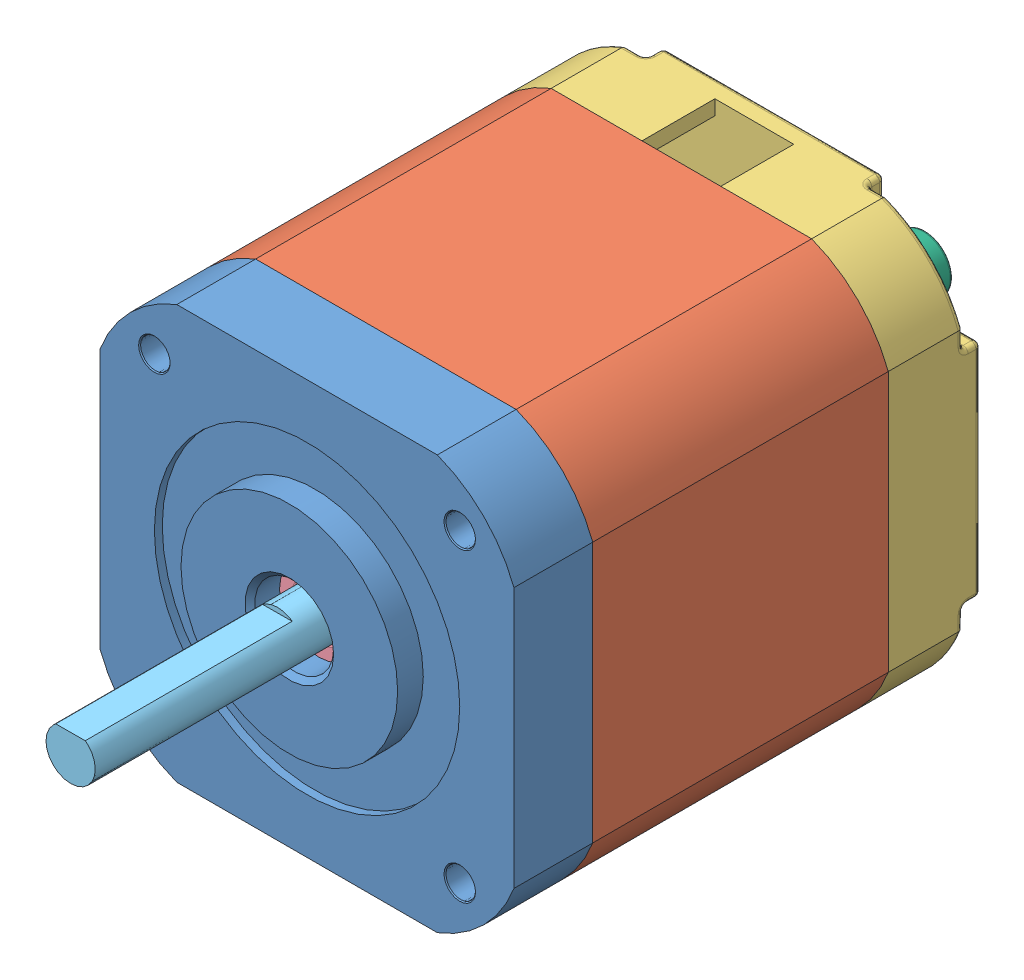
SolidWorks assembly Nema 17, configuration Default. Lengths in mm.
Overall size (42 42 71.95).
10 component instances, 6 part files, 23 mates.
Components (placement in the parent):
- Part1^Nema 17-1: Part1^Nema 17 [Default] at origin size (42 42 10.8) (virtual)
- Part2^Nema 17-1: Part2^Nema 17 [Default] at (0 0 -8) x (-1 0 0) z (0 0 -1) size (42 42 30) (virtual)
- Part3^Nema 17-1: Part3^Nema 17 [Default] at (0 0 -38) x (-1 0 0) z (0 0 -1) size (42 42 10.2) (virtual)
- radial ball bearing_68_din-1: radial ball bearing_68_din [DIN 625 - 625 - 8,SI,NC,8_68] at (0 0 -3.7) x (0 0 -1) z (1 0 0) size (5 16 16)
- radial ball bearing_68_din-2: radial ball bearing_68_din [DIN 625 - 625 - 8,SI,NC,8_68] at (0 0 -41.9) x (0 0 -1) z (0.878806 0.477179 0) size (5 16 16)
- Part4^Nema 17-1: Part4^Nema 17 [Default] at (0 0 -44.5) x (0.99998 0.006291 0) z (0 0 1) size (5 5 68.5) (virtual)
- pan head cross recess screw_din-3: pan head cross recess screw_din [ISO 7045 - M3 x 40 - Z --- 30N] at (-15.5 15.5 -48) x (0 0 1) z (-1 0 0) size (42.35 5.6 5.6)
- pan head cross recess screw_din-4: pan head cross recess screw_din [ISO 7045 - M3 x 40 - Z --- 30N] at (-15.5 -15.5 -48) x (0 0 1) z (-1 0 0) size (42.35 5.6 5.6)
- pan head cross recess screw_din-5: pan head cross recess screw_din [ISO 7045 - M3 x 40 - Z --- 30N] at (15.5 -15.5 -48) x (0 0 1) z (-1 0 0) size (42.35 5.6 5.6)
- pan head cross recess screw_din-6: pan head cross recess screw_din [ISO 7045 - M3 x 40 - Z --- 30N] at (15.5 15.5 -48) x (0 0 1) z (-1 0 0) size (42.35 5.6 5.6)
Mates (geometry in assembly coordinates):
- Coincident4: coordinate: point of Part1^Nema 17-1; point of assembly
- InPlace2: in place: plane of Part1^Nema 17-1 through (0 0 -8) normal (0 0 -1); plane of Part2^Nema 17-1 through (0 0 -8) normal (0 0 -1); moOrthogonalPlaneRef_w of Part1^Nema 17-1 through (0 0 -8) normal (0 0 -1); unknown of Part2^Nema 17-1; plane of Part1^Nema 17-1 through (0 0 -8) normal (0 0 -1); plane of Part2^Nema 17-1 through (0 0 -8) normal (-1 0 0); plane of Part1^Nema 17-1 through (0 0 -8) normal (0 0 -1); unknown of Part2^Nema 17-1
- Coincident5: coincident aligned: plane of Part1^Nema 17-1; plane of Part2^Nema 17-1
- Coincident6: coincident aligned: moOrthogonalPlaneRef_w of Part1^Nema 17-1 through (0 0 -8) normal (0 1 0); plane of Part2^Nema 17-1
- Coincident7: coincident anti-aligned: moOrthogonalPlaneRef_w of Part1^Nema 17-1 through (0 0 -8) normal (1 0 0); plane of Part2^Nema 17-1 through (0 0 -8) normal (-1 0 0)
- InPlace3: in place: plane of Part2^Nema 17-1 through (0 0 -38) normal (0 0 -1); plane of Part3^Nema 17-1 through (0 0 -38) normal (0 0 -1); plane of Part2^Nema 17-1 through (0 0 -38) normal (0 0 -1); unknown of Part3^Nema 17-1; plane of Part2^Nema 17-1 through (0 0 -38) normal (0 0 -1); plane of Part3^Nema 17-1 through (0 0 -38) normal (-1 0 0); plane of Part2^Nema 17-1 through (0 0 -38) normal (0 0 -1); unknown of Part3^Nema 17-1
- Coincident8: coincident aligned: plane of Part2^Nema 17-1; plane of Part3^Nema 17-1
- Coincident9: coincident aligned: moOrthogonalPlaneRef_w of Part2^Nema 17-1 through (0 0 -38) normal (0 1 0); plane of Part3^Nema 17-1
- Coincident10: coincident anti-aligned: moOrthogonalPlaneRef_w of Part2^Nema 17-1 through (0 0 -38) normal (1 0 0); plane of Part3^Nema 17-1 through (0 0 -38) normal (-1 0 0)
- Concentric1: concentric anti-aligned: cylinder of Part1^Nema 17-1 through (0 0 -9) axis (0 0 1) radius 8; cylinder of radial ball bearing_68_din-1 through (0 0 16.9375) axis (0 0 -1) radius 8
- Coincident11: coincident anti-aligned: plane of Part1^Nema 17-1 through (0 0 -1.2) normal (0 0 -1); plane of radial ball bearing_68_din-1 through (0 6.35 -1.2) normal (0 0 1)
- Concentric2: concentric aligned: cylinder of Part3^Nema 17-1 through (0 0 -37.2) axis (0 0 -1) radius 8; cylinder of radial ball bearing_68_din-2 through (0 0 -21.2625) axis (0 0 -1) radius 8
- Distance2: distance = 1 mm anti-aligned: plane of Part3^Nema 17-1 through (0 0 -45.4) normal (0 0 1); plane of radial ball bearing_68_din-2 through (-3.6743 6.7668 -44.4) normal (0 0 -1)
- Concentric3: concentric aligned: cylinder of radial ball bearing_68_din-1 through (0 0 16.9375) axis (0 0 -1) radius 2.5; cylinder of Part4^Nema 17-1 through (0 0 24) axis (0 0 -1) radius 2.5
- Distance1: distance = 24 mm aligned: plane of Part1^Nema 17-1 through (0 0 0) normal (0 0 1); plane of Part4^Nema 17-1 through (0 0 24) normal (0 0 1)
- Concentric4: concentric anti-aligned: cone of Part3^Nema 17-1 through (-15.5 15.5 -45.6) axis (0 0 1); cylinder of pan head cross recess screw_din-3 through (-15.5 15.5 -73.4) axis (0 0 -1) radius 2.8
- Coincident17: coincident anti-aligned: plane of Part3^Nema 17-1 through (0 0 -45.6) normal (0 0 -1); plane of pan head cross recess screw_din-3 through (-15.5 17 -45.6) normal (0 0 1)
- Concentric5: concentric anti-aligned: cone of Part3^Nema 17-1 through (-15.5 -15.5 -45.6) axis (0 0 1); cylinder of pan head cross recess screw_din-4 through (-15.5 -15.5 -73.4) axis (0 0 -1) radius 2.8
- Coincident18: coincident anti-aligned: plane of Part3^Nema 17-1 through (0 0 -45.6) normal (0 0 -1); plane of pan head cross recess screw_din-4 through (-15.5 -14 -45.6) normal (0 0 1)
- Concentric6: concentric anti-aligned: cone of Part3^Nema 17-1 through (15.5 -15.5 -45.6) axis (0 0 1); cylinder of pan head cross recess screw_din-5 through (15.5 -15.5 -73.4) axis (0 0 -1) radius 2.8
- Coincident19: coincident anti-aligned: plane of Part3^Nema 17-1 through (0 0 -45.6) normal (0 0 -1); plane of pan head cross recess screw_din-5 through (15.5 -14 -45.6) normal (0 0 1)
- Concentric7: concentric anti-aligned: cone of Part3^Nema 17-1 through (15.5 15.5 -45.6) axis (0 0 1); cylinder of pan head cross recess screw_din-6 through (15.5 15.5 -73.4) axis (0 0 -1) radius 2.8
- Coincident20: coincident anti-aligned: plane of Part3^Nema 17-1 through (0 0 -45.6) normal (0 0 -1); plane of pan head cross recess screw_din-6 through (15.5 17 -45.6) normal (0 0 1)
